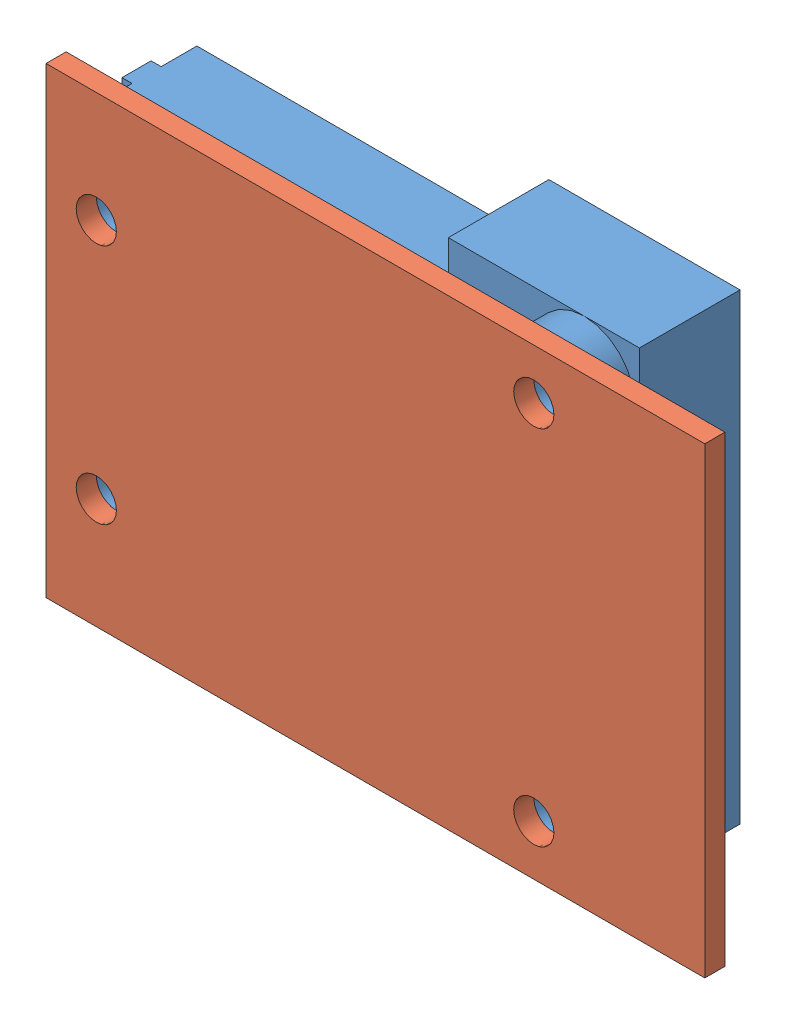
SolidWorks assembly Assemblage11, configuration Default. Lengths in mm.
Overall size (66.5 46 15).
2 component instances, 2 part files, 2 mates.
Components (placement in the parent):
- UsbBoardSupport-1: UsbBoardSupport [Défaut] at (-10.4371 31.1411 50.6649) size (55 46 13)
- UsbBoard-1: UsbBoard [Défaut] at (-37.4371 8.1411 63.6649) size (65.5 46 2)
Mates (geometry in assembly coordinates):
- Coïncidente2: coincident anti-aligned: plane of UsbBoardSupport-1 through (-32.4371 43.1411 63.6649) normal (0 0 1); plane of UsbBoard-1 through (-57.5336 -6.9242 63.6649) normal (0 0 -1)
- Coaxiale1: concentric aligned: cylinder of UsbBoardSupport-1 through (-32.4371 43.1411 50.6649) axis (0 0 1) radius 2; cylinder of UsbBoard-1 through (-32.4371 43.1411 63.6649) axis (0 0 1) radius 2
